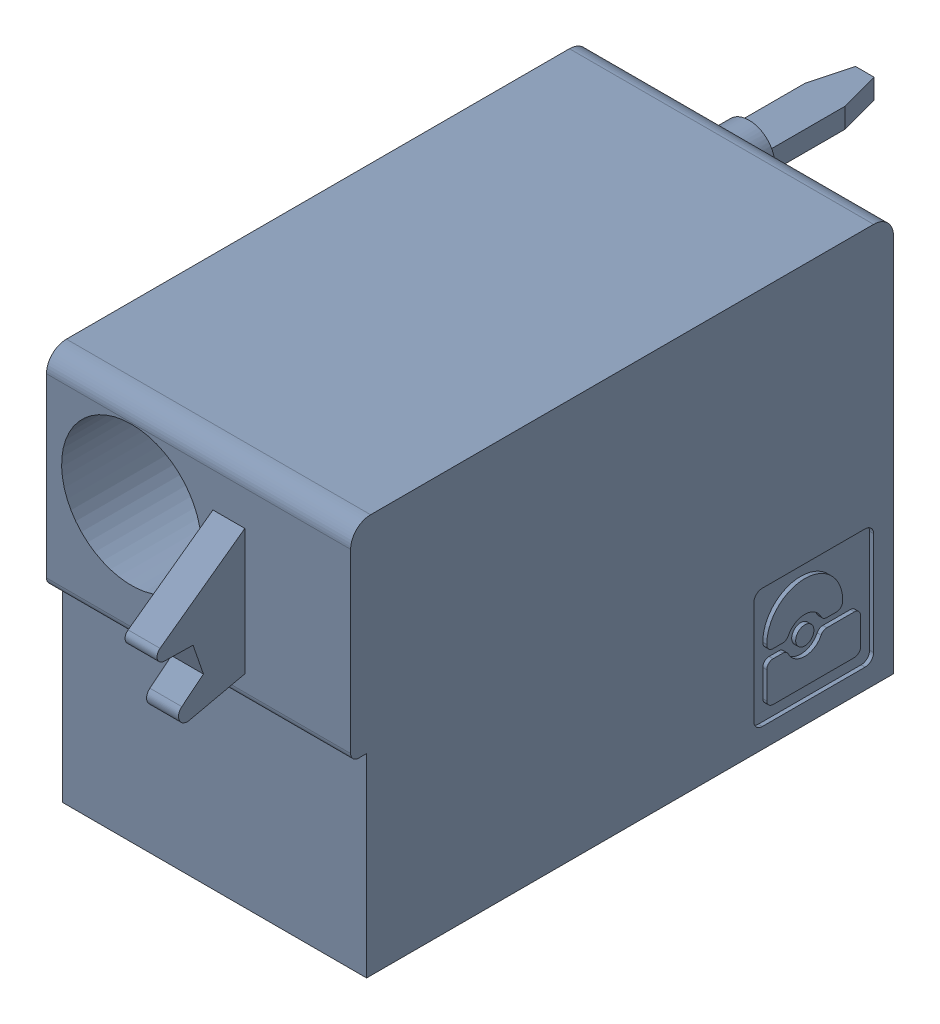
SolidWorks assembly J67, configuration Default. Lengths in mm.
Overall size (7.62 10 19.2).
2 component instances, 1 part files, 0 mates.
Components (placement in the parent):
- 1790487-1: 1790487 [Default] at (180.745 -5.67 -10.6) x (0 1 0) z (1 0 0) size (10 19.2 7.62)
  - ffkdsa1-v2-7.62-1: ffkdsa1-v2-7.62 [Default] at (-15.6914 -27.508 9.12) x (0 -1 0) z (0 0 1) size (19.2 10 7.62)
